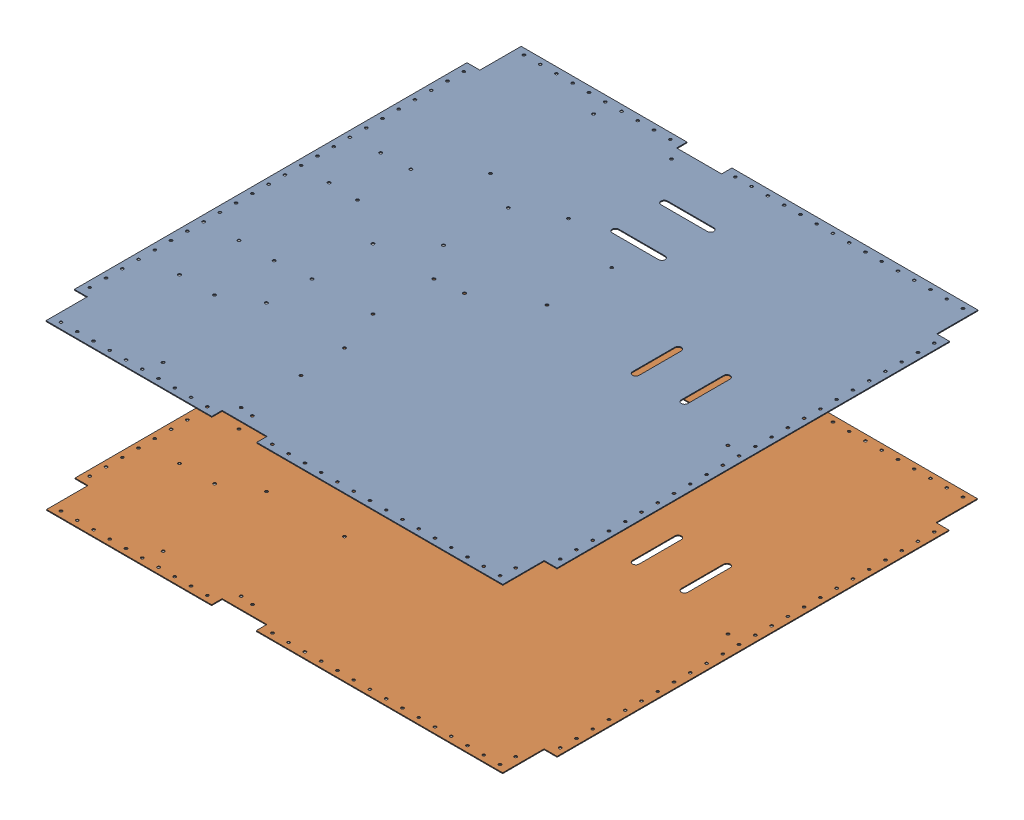
SolidWorks assembly BaseplateV2HolePlacement, configuration Default. Lengths in mm.
Overall size (593.65 202.03 584.45).
2 component instances, 2 part files, 3 mates.
Components (placement in the parent):
- Baseplate-1: Baseplate [Default] at origin size (593.65 1.02 584.45)
- BaseplateV2-1: BaseplateV2 [Default] at (753.7 -202.032 -12.8) x (0 0 -1) z (0 1 0) size (584 593 1.02)
Mates (geometry in assembly coordinates):
- Concentric2: concentric anti-aligned: circle of Baseplate-1; circle of BaseplateV2-1
- Concentric3: concentric anti-aligned: circle of Baseplate-1; circle of BaseplateV2-1
- Distance1: distance = 200 mm anti-aligned: plane of BaseplateV2-1 through (753.7 -201.016 -12.8) normal (0 1 0); plane of Baseplate-1 through (0 -1.016 0) normal (0 -1 0)
